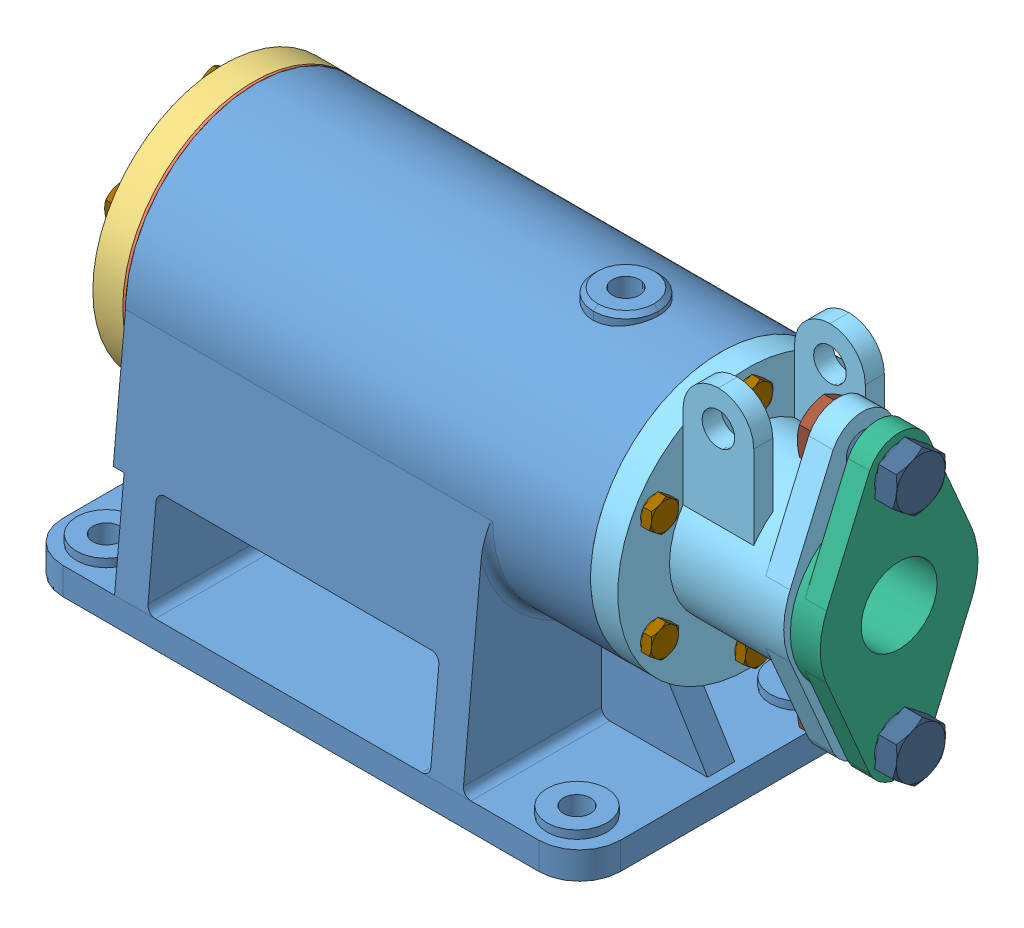
SolidWorks assembly Сборка корпуса - МЛИ2.01.00, configuration По умолчанию. Lengths in mm.
Overall size (274.39 155 112).
24 component instances, 11 part files, 52 mates.
Components (placement in the parent):
- Корпус - МЛИ2.00.01-1: Корпус - МЛИ2.00.01 [По умолчанию] at origin size (205 146 112)
- Прокладка - МЛИ2.00.07-1: Прокладка - МЛИ2.00.07 [По умолчанию] at (29 95 56) x (0 0 -1) z (1 0 0) size (96 96 1)
- Крышка - МЛИ2.00.02-3: Крышка - МЛИ2.00.02 [По умолчанию] at (18 95 56) x (0 0 -1) z (1 0 0) size (96 96 28)
- Кольцо уплотнительное-1: Кольцо уплотнительное [По умолчанию] at (35.9 95 56) x (-1 0 0) z (0 -0.955563 0.294787) size (5.8 65.6 65.6)
- Стакан - МЛИ2.00.06-1: Стакан - МЛИ2.00.06 [По умолчанию] at (211 95 56) x (0 0 1) z (-1 0 0) size (96 115 56)
- Фланец - МЛИ2.00.03-2: Фланец - МЛИ2.00.03 [По умолчанию] at (224.4398 95 56) x (0 0 -1) z (-1 0 0) size (58 110 44)
- Войлок-1: Войлок [По умолчанию] at (227.3473 95 56) x (-1 0 0) z (0 -0.960759 0.277384) size (27 45 45)
- Кольцо уплотнительное 1-1: Кольцо уплотнительное 1 [По умолчанию] at (182.9 95 56) size (5.8 33.8 33.8)
- hex screw gradeab_iso_var1-14: hex screw gradeab_iso_var1 [ISO 4017 - M6 x 25-N] at (14 135 56) size (29 11.55 10)
- hex screw gradeab_iso_var1-15: hex screw gradeab_iso_var1 [ISO 4017 - M6 x 25-N] at (14 115 90.641) size (29 11.55 10)
- hex screw gradeab_iso_var1-16: hex screw gradeab_iso_var1 [ISO 4017 - M6 x 25-N] at (14 75 90.641) size (29 11.55 10)
- hex screw gradeab_iso_var1-17: hex screw gradeab_iso_var1 [ISO 4017 - M6 x 25-N] at (14 55 56) size (29 11.55 10)
- hex screw gradeab_iso_var1-18: hex screw gradeab_iso_var1 [ISO 4017 - M6 x 25-N] at (14 75 21.359) size (29 11.55 10)
- hex screw gradeab_iso_var1-19: hex screw gradeab_iso_var1 [ISO 4017 - M6 x 25-N] at (14 115 21.359) size (29 11.55 10)
- hex screw gradeab_iso_var1-22: hex screw gradeab_iso_var1 [ISO 4017 - M6 x 25-N] at (215 115 90.641) x (-1 0 0) z (0 0.924225 0.381849) size (29 11.55 10)
- hex screw gradeab_iso_var1-23: hex screw gradeab_iso_var1 [ISO 4017 - M6 x 25-N] at (215 75 90.641) x (-1 0 0) z (0 0.924225 0.381849) size (29 11.55 10)
- hex screw gradeab_iso_var1-24: hex screw gradeab_iso_var1 [ISO 4017 - M6 x 25-N] at (215 55 56) x (-1 0 0) z (0 0.924225 0.381849) size (29 11.55 10)
- hex screw gradeab_iso_var1-25: hex screw gradeab_iso_var1 [ISO 4017 - M6 x 25-N] at (215 75 21.359) x (-1 0 0) z (0 0.924225 0.381849) size (29 11.55 10)
- hex screw gradeab_iso_var1-26: hex screw gradeab_iso_var1 [ISO 4017 - M6 x 25-N] at (215 115 21.359) x (-1 0 0) z (0 0.924225 0.381849) size (29 11.55 10)
- hex screw gradeab_iso_var1-27: hex screw gradeab_iso_var1 [ISO 4017 - M6 x 25-N] at (215 135 56) x (-1 0 0) z (0 0.924225 0.381849) size (29 11.55 10)
- hex screw gradec_iso_var1-4: hex screw gradec_iso_var1 [ISO 4018 - M12 x 30-WN] at (274.3898 52 56) x (-1 0 0) z (0 0.924225 0.381849) size (37.95 20.78 18)
- hex screw gradec_iso_var1-5: hex screw gradec_iso_var1 [ISO 4018 - M12 x 30-WN] at (274.3898 138 56) x (-1 0 0) z (0 0.924225 0.381849) size (37.95 20.78 18)
- hex thin nut chamfered gradeab_iso_var1-4: hex thin nut chamfered gradeab_iso_var1 [ISO - 4035 - M12 - N] at (238 52 56) x (0 0 1) z (-1 0 0) size (18 20.78 6)
- hex thin nut chamfered gradeab_iso_var1-5: hex thin nut chamfered gradeab_iso_var1 [ISO - 4035 - M12 - N] at (238 138 56) x (0 0 1) z (-1 0 0) size (18 20.78 6)
Mates (geometry in assembly coordinates):
- Совпадение1: coincident anti-aligned: plane of Корпус - МЛИ2.00.01-1 through (30 0 0) normal (-1 0 0); plane of Прокладка - МЛИ2.00.07-1 through (30 95 56) normal (1 0 0)
- Концентричный1: concentric aligned: cylinder of Корпус - МЛИ2.00.01-1 through (49 135 56) axis (-1 0 0) radius 3; cylinder of Прокладка - МЛИ2.00.07-1 through (30 135 56) axis (-1 0 0) radius 3.5
- Концентричный2: concentric aligned: cylinder of Корпус - МЛИ2.00.01-1 through (49 55 56) axis (-1 0 0) radius 3; cylinder of Прокладка - МЛИ2.00.07-1 through (30 55 56) axis (-1 0 0) radius 3.5
- Концентричный3: concentric anti-aligned: cylinder of Крышка - МЛИ2.00.02-3 through (46 95 56) axis (-1 0 0) radius 33; axis of Кольцо уплотнительное-1 through (17.3093 95 56) axis (1 0 0)
- Касательность3: tangent anti-aligned: plane of Крышка - МЛИ2.00.02-3 through (33 95 56) normal (1 0 0); torus of Кольцо уплотнительное-1
- Параллельность1: parallel anti-aligned: plane of Прокладка - МЛИ2.00.07-1 through (29 95 56) normal (-1 0 0); plane of Крышка - МЛИ2.00.02-3 through (29 95 56) normal (1 0 0)
- Концентричный8: concentric aligned: cylinder of Корпус - МЛИ2.00.01-1 through (49 135 56) axis (-1 0 0) radius 3; cylinder of Крышка - МЛИ2.00.02-3 through (29 135 56) axis (-1 0 0) radius 3
- Концентричный9: concentric aligned: cylinder of Корпус - МЛИ2.00.01-1 through (49 75 90.641) axis (-1 0 0) radius 3; cylinder of Крышка - МЛИ2.00.02-3 through (29 75 90.641) axis (-1 0 0) radius 3
- Граничное расстояние1: limit distance = 0 mm anti-aligned: plane of Крышка - МЛИ2.00.02-3 through (29 95 56) normal (1 0 0); plane of Прокладка - МЛИ2.00.07-1 through (29 95 56) normal (-1 0 0)
- Совпадение2: coincident anti-aligned: plane of Корпус - МЛИ2.00.01-1 through (201 0 0) normal (1 0 0); plane of Стакан - МЛИ2.00.06-1 through (201 95 56) normal (-1 0 0)
- Концентричный10: concentric anti-aligned: cylinder of Корпус - МЛИ2.00.01-1 through (182 75 21.359) axis (1 0 0) radius 3; cylinder of Стакан - МЛИ2.00.06-1 through (211 75 21.359) axis (-1 0 0) radius 3.5
- Концентричный11: concentric anti-aligned: cylinder of Корпус - МЛИ2.00.01-1 through (182 135 56) axis (1 0 0) radius 3; cylinder of Стакан - МЛИ2.00.06-1 through (211 135 56) axis (-1 0 0) radius 3.5
- Концентричный13: concentric aligned: cylinder of Стакан - МЛИ2.00.06-1 through (197 95 56) axis (1 0 0) radius 22.5; cylinder of Фланец - МЛИ2.00.03-2 through (222.4398 95 56) axis (1 0 0) radius 22.5
- Граничное расстояние3: limit distance = 2.4398 mm anti-aligned: plane of Фланец - МЛИ2.00.03-2 through (255.4398 95 56) normal (-1 0 0); plane of Стакан - МЛИ2.00.06-1 through (253 52 56) normal (1 0 0)
- Концентричный14: concentric aligned: cylinder of Стакан - МЛИ2.00.06-1 through (244 138 56) axis (1 0 0) radius 6; cylinder of Фланец - МЛИ2.00.03-2 through (257.4398 138 56) axis (1 0 0) radius 6
- Концентричный15: concentric aligned: cylinder of Стакан - МЛИ2.00.06-1 through (197 95 56) axis (1 0 0) radius 22.5; cylinder of Войлок-1 through (227.3473 95 56) axis (1 0 0) radius 22.5
- Совпадение6: coincident aligned: cone of Фланец - МЛИ2.00.03-2 through (227.3473 95 56) axis (1 0 0); cone of Войлок-1 through (227.3473 95 56) axis (1 0 0)
- Граничное расстояние4: limit distance = 5.3473 mm anti-aligned: plane of Войлок-1 through (200.3473 91.1166 42.5494) normal (-1 0 0); plane of Корпус - МЛИ2.00.01-1 through (195 95 56) normal (1 0 0)
- Совпадение8: coincident anti-aligned: line of Корпус - МЛИ2.00.01-1 through (165 95 56) axis (1 0 0); line of Кольцо уплотнительное 1-1 through (192.5302 95 56) axis (-1 0 0)
- Касательность5: tangent anti-aligned: plane of Корпус - МЛИ2.00.01-1 through (180 95 56) normal (1 0 0); torus of Кольцо уплотнительное 1-1
- Концентричный161: concentric aligned: cylinder of Крышка - МЛИ2.00.02-3 through (29 135 56) axis (-1 0 0) radius 3; cylinder of hex screw gradeab_iso_var1-14 through (14 135 56) axis (-1 0 0) radius 5
- Совпадение91: coincident anti-aligned: plane of Крышка - МЛИ2.00.02-3 through (18 95 56) normal (-1 0 0); plane of hex screw gradeab_iso_var1-14 through (18 140.7735 56) normal (1 0 0)
- Концентричный171: concentric aligned: cylinder of Крышка - МЛИ2.00.02-3 through (29 115 90.641) axis (-1 0 0) radius 3; cylinder of hex screw gradeab_iso_var1-15 through (14 115 90.641) axis (-1 0 0) radius 5
- Совпадение101: coincident anti-aligned: plane of Крышка - МЛИ2.00.02-3 through (18 95 56) normal (-1 0 0); plane of hex screw gradeab_iso_var1-15 through (18 120.7735 90.641) normal (1 0 0)
- Концентричный181: concentric aligned: cylinder of Крышка - МЛИ2.00.02-3 through (29 75 90.641) axis (-1 0 0) radius 3; cylinder of hex screw gradeab_iso_var1-16 through (14 75 90.641) axis (-1 0 0) radius 5
- Совпадение111: coincident anti-aligned: plane of Крышка - МЛИ2.00.02-3 through (18 95 56) normal (-1 0 0); plane of hex screw gradeab_iso_var1-16 through (18 80.7735 90.641) normal (1 0 0)
- Концентричный191: concentric aligned: cylinder of Крышка - МЛИ2.00.02-3 through (29 55 56) axis (-1 0 0) radius 3; cylinder of hex screw gradeab_iso_var1-17 through (14 55 56) axis (-1 0 0) radius 5
- Совпадение121: coincident anti-aligned: plane of Крышка - МЛИ2.00.02-3 through (18 95 56) normal (-1 0 0); plane of hex screw gradeab_iso_var1-17 through (18 60.7735 56) normal (1 0 0)
- Концентричный201: concentric aligned: cylinder of Крышка - МЛИ2.00.02-3 through (29 75 21.359) axis (-1 0 0) radius 3; cylinder of hex screw gradeab_iso_var1-18 through (14 75 21.359) axis (-1 0 0) radius 5
- Совпадение131: coincident anti-aligned: plane of Крышка - МЛИ2.00.02-3 through (18 95 56) normal (-1 0 0); plane of hex screw gradeab_iso_var1-18 through (18 80.7735 21.359) normal (1 0 0)
- Концентричный211: concentric aligned: cylinder of Крышка - МЛИ2.00.02-3 through (29 115 21.359) axis (-1 0 0) radius 3; cylinder of hex screw gradeab_iso_var1-19 through (14 115 21.359) axis (-1 0 0) radius 5
- Совпадение141: coincident anti-aligned: plane of Крышка - МЛИ2.00.02-3 through (18 95 56) normal (-1 0 0); plane of hex screw gradeab_iso_var1-19 through (18 120.7735 21.359) normal (1 0 0)
- Концентричный231: concentric anti-aligned: cylinder of Стакан - МЛИ2.00.06-1 through (211 115 90.641) axis (-1 0 0) radius 3.5; cylinder of hex screw gradeab_iso_var1-22 through (215 115 90.641) axis (1 0 0) radius 5
- Совпадение161: coincident anti-aligned: plane of Стакан - МЛИ2.00.06-1 through (211 95 56) normal (1 0 0); plane of hex screw gradeab_iso_var1-22 through (211 112.7954 95.977) normal (-1 0 0)
- Концентричный241: concentric anti-aligned: cylinder of Стакан - МЛИ2.00.06-1 through (211 75 90.641) axis (-1 0 0) radius 3.5; cylinder of hex screw gradeab_iso_var1-23 through (215 75 90.641) axis (1 0 0) radius 5
- Совпадение171: coincident anti-aligned: plane of Стакан - МЛИ2.00.06-1 through (211 95 56) normal (1 0 0); plane of hex screw gradeab_iso_var1-23 through (211 72.7954 95.977) normal (-1 0 0)
- Концентричный251: concentric anti-aligned: cylinder of Стакан - МЛИ2.00.06-1 through (211 55 56) axis (-1 0 0) radius 3.5; cylinder of hex screw gradeab_iso_var1-24 through (215 55 56) axis (1 0 0) radius 5
- Совпадение181: coincident anti-aligned: plane of Стакан - МЛИ2.00.06-1 through (211 95 56) normal (1 0 0); plane of hex screw gradeab_iso_var1-24 through (211 52.7954 61.336) normal (-1 0 0)
- Концентричный261: concentric anti-aligned: cylinder of Стакан - МЛИ2.00.06-1 through (211 75 21.359) axis (-1 0 0) radius 3.5; cylinder of hex screw gradeab_iso_var1-25 through (215 75 21.359) axis (1 0 0) radius 5
- Совпадение191: coincident anti-aligned: plane of Стакан - МЛИ2.00.06-1 through (211 95 56) normal (1 0 0); plane of hex screw gradeab_iso_var1-25 through (211 72.7954 26.695) normal (-1 0 0)
- Концентричный271: concentric anti-aligned: cylinder of Стакан - МЛИ2.00.06-1 through (211 115 21.359) axis (-1 0 0) radius 3.5; cylinder of hex screw gradeab_iso_var1-26 through (215 115 21.359) axis (1 0 0) radius 5
- Совпадение201: coincident anti-aligned: plane of Стакан - МЛИ2.00.06-1 through (211 95 56) normal (1 0 0); plane of hex screw gradeab_iso_var1-26 through (211 112.7954 26.695) normal (-1 0 0)
- Концентричный281: concentric anti-aligned: cylinder of Стакан - МЛИ2.00.06-1 through (211 135 56) axis (-1 0 0) radius 3.5; cylinder of hex screw gradeab_iso_var1-27 through (215 135 56) axis (1 0 0) radius 5
- Совпадение211: coincident anti-aligned: plane of Стакан - МЛИ2.00.06-1 through (211 95 56) normal (1 0 0); plane of hex screw gradeab_iso_var1-27 through (211 132.7954 61.336) normal (-1 0 0)
- Концентричный291: concentric aligned: cylinder of Фланец - МЛИ2.00.03-2 through (257.4398 52 56) axis (1 0 0) radius 6; cylinder of hex screw gradec_iso_var1-4 through (274.3898 52 56) axis (1 0 0) radius 6
- Совпадение221: coincident anti-aligned: plane of Фланец - МЛИ2.00.03-2 through (266.4398 138 56) normal (1 0 0); plane of hex screw gradec_iso_var1-4 through (266.4398 35.364 49.1267) normal (-1 0 0)
- Концентричный301: concentric aligned: cylinder of Фланец - МЛИ2.00.03-2 through (257.4398 138 56) axis (1 0 0) radius 6; cylinder of hex screw gradec_iso_var1-5 through (274.3898 138 56) axis (1 0 0) radius 6
- Совпадение231: coincident anti-aligned: plane of Фланец - МЛИ2.00.03-2 through (266.4398 138 56) normal (1 0 0); plane of hex screw gradec_iso_var1-5 through (266.4398 121.364 49.1267) normal (-1 0 0)
- Концентричный31: concentric anti-aligned: cylinder of hex screw gradec_iso_var1-4 through (274.3898 52 56) axis (1 0 0) radius 6; cylinder of hex thin nut chamfered gradeab_iso_var1-4 through (263.0375 52 56) axis (-1 0 0) radius 6
- Совпадение24: coincident anti-aligned: plane of Стакан - МЛИ2.00.06-1 through (244 52 56) normal (-1 0 0); plane of hex thin nut chamfered gradeab_iso_var1-4 through (244 62.3923 56) normal (1 0 0)
- Концентричный32: concentric anti-aligned: cylinder of hex screw gradec_iso_var1-5 through (274.3898 138 56) axis (1 0 0) radius 6; cylinder of hex thin nut chamfered gradeab_iso_var1-5 through (263.0375 138 56) axis (-1 0 0) radius 6
- Совпадение25: coincident anti-aligned: plane of Стакан - МЛИ2.00.06-1 through (244 52 56) normal (-1 0 0); plane of hex thin nut chamfered gradeab_iso_var1-5 through (244 148.3923 56) normal (1 0 0)
